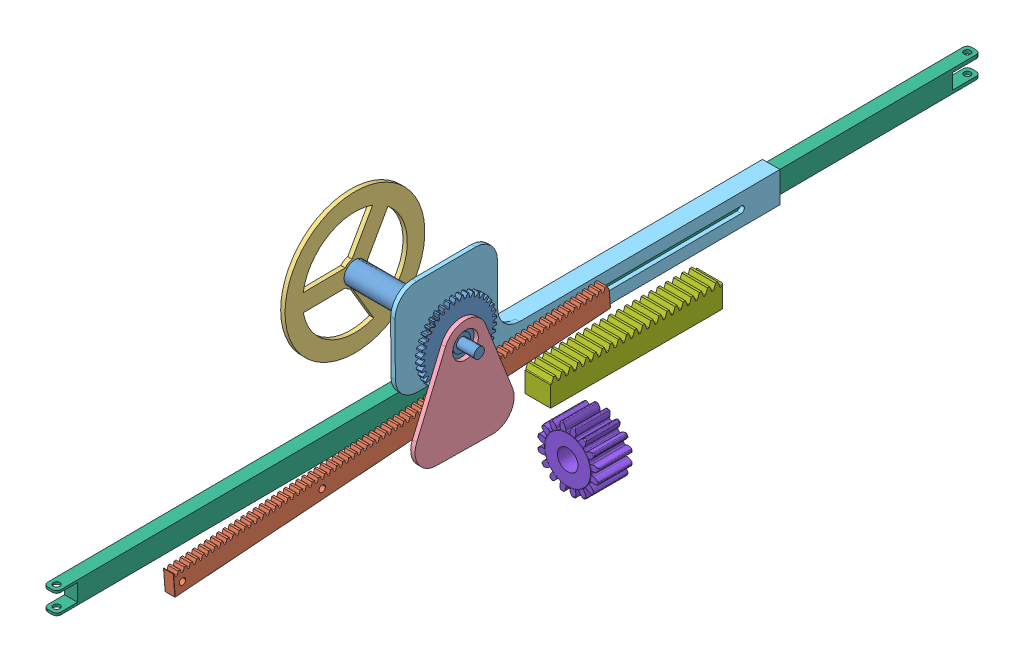
SolidWorks assembly ProgressiveSteering, configuration Default. Lengths in mm.
Overall size (91.09 164.43 537.27).
8 component instances, 8 part files, 22 mates.
Components (placement in the parent):
- SI_sdpsi_s1268z-024s040-2: SI_sdpsi_s1268z-024s040 [Default] at (1.5875 -10.9322 -6.4635) x (1 0 0) z (0 0.508936 -0.860805) size (65.8 44.45 44.45)
- SI_sdpsi_s1811y-rc-1a-1: SI_sdpsi_s1811y-rc-1a [Default] at (1.5875 -40.523 33.7269) x (0 -0.075237 0.997166) z (-1 0 0) size (254.01 12.19 10.01)
- steering wheel-1: steering wheel [Default] at (-55.245 0 0) x (0 -0.508936 0.860805) z (1 0 0) size (81.28 81.28 2.54)
- Part1^ProgressiveSteering-1: Part1^ProgressiveSteering [Default] at (7.0409 -36.8131 39.9889) x (0 0.013013 0.999915) z (-1 0 0) size (57.65 65.11 10.92) (virtual)
- slot-2: slot [Default] at (-16.3313 -50.6873 -22.7502) x (0 -0.006116 0.999981) z (-1 0 0) size (223.58 68.29 10.16)
- steering bar-1: steering bar [Default] at (-3.8735 -39.6305 140.3381) x (-1 0 0) z (0 0.006116 -0.999981) size (7.62 12.7 537.2)
- KHK-US_SRAF1_5-1000.stp-1: KHK-US_SRAF1_5-1000.stp [Default] at (-41.18 -102.411 -596.1689) size (16 15.5 100.5)
- 2664N392_Metal Gear - 20 Degree Pressure Angle-1: 2664N392_Metal Gear - 20 Degree Pressure Angle [2664N392] at (20.0282 -85.4641 -57.9863) size (35.44 35.44 20.17)
Mates (geometry in assembly coordinates):
- Coincident6: coincident anti-aligned: circle of SI_sdpsi_s1268z-024s040-2
- Coincident8: coincident: point of SI_sdpsi_s1268z-024s040-2; point of assembly
- Coincident13: coincident anti-aligned: plane of SI_sdpsi_s1268z-024s040-2 through (1.5875 -10.9322 -6.4635) normal (1 0 0); plane of SI_sdpsi_s1811y-rc-1a-1 through (1.5875 -40.523 33.7269) normal (-1 0 0)
- Distance1: distance = 21.082 mm: line of assembly; point of SI_sdpsi_s1268z-024s040-2; line of SI_sdpsi_s1811y-rc-1a-1 through (1.5875 -44.8095 163.1218) axis (0 0.075237 -0.997166)
- RackPinionMate2: rack pinion = 45.212 mm: line of SI_sdpsi_s1811y-rc-1a-1 through (-1.3335 -36.9296 -93.2356) axis (0 -0.075237 0.997166); cylinder of SI_sdpsi_s1268z-024s040-2 through (0 -10.9322 -6.4635) axis (1 0 0) radius 22.225
- Concentric6: concentric anti-aligned: cylinder of SI_sdpsi_s1268z-024s040-2 through (-50.8 0 0) axis (1 0 0) radius 6.35; cylinder of steering wheel-1 through (-50.8 0 0) axis (-1 0 0) radius 7.62
- Coincident21: coincident anti-aligned: plane of SI_sdpsi_s1268z-024s040-2 through (-50.8 0 0) normal (-1 0 0); plane of steering wheel-1 through (-50.8 0 0) normal (1 0 0)
- Coincident22: coincident: line of SI_sdpsi_s1268z-024s040-2 through (0 -29.8358 -17.6399) axis (0 0.860805 0.508936); plane of steering wheel-1 through (-55.245 0 0) normal (0 -0.508936 0.860805)
- Distance6: distance = 3.175 mm aligned: plane of slot-1 through (7.0485 -3.175 -260.805) normal (0 1 0)
- Concentric8: concentric anti-aligned: cylinder of Part1^ProgressiveSteering-1 through (96.8058 -27.6971 14.6022) axis (-1 0 0) radius 7.5; cylinder of 4668K121_Permanently Lubricated Stainless Steel Ball Bearing-3 through (4.5085 -27.4311 18.3355) axis (1 0 0) radius 7.5
- Coincident29: coincident anti-aligned: plane of Part1^ProgressiveSteering-1 through (7.0409 -10.9322 -6.4635) normal (1 0 0); plane of 4668K121_Permanently Lubricated Stainless Steel Ball Bearing-3 through (4.5085 -30.9404 20.5036) normal (1 0 0)
- Tangent2: tangent anti-aligned: plane of SI_sdpsi_s1811y-rc-1a-1 through (4.5085 -37.0467 -93.3718) normal (0 -0.997166 -0.075237); cylinder of 4668K121_Permanently Lubricated Stainless Steel Ball Bearing-3 through (4.5085 -27.4311 18.3355) axis (1 0 0) radius 7.5
- Distance7: distance = 25.4 mm: plane of slot-1 through (7.0485 -34.2791 -85.7379) normal (1 0 0); plane of SI_sdpsi_s1811y-rc-1a-1 through (-1.3335 -14.2012 -44.3268) normal (-1 0 0)
- Distance8: distance = 12.7 mm: plane of assembly through (0 0 0) normal (1 0 0); plane of assembly; plane of slot-1 through (7.0485 -34.2791 -85.7379) normal (1 0 0)
- Concentric9: concentric aligned: circle of SI_sdpsi_s1268z-024s040-2; circle of Part1^ProgressiveSteering-1
- Coincident32: coincident anti-aligned: plane of SI_sdpsi_s1811y-rc-1a-1 through (4.5085 -40.523 33.7269) normal (1 0 0); plane of Part1^ProgressiveSteering-1 through (4.5085 -10.9322 -6.4635) normal (-1 0 0)
- Coincident35: coincident anti-aligned: plane of SI_sdpsi_s1811y-rc-1a-1 through (-1.3335 -40.523 33.7269) normal (-1 0 0); plane of slot-2 through (-1.3335 -50.6873 -22.7502) normal (1 0 0)
- Concentric10: concentric aligned: circle of SI_sdpsi_s1268z-024s040-2; circle of slot-2
- Slot1: slot anti-aligned: cylinder of SI_sdpsi_s1811y-rc-1a-1 through (-5.4915 -31.8825 -88.2188) axis (1 0 0) radius 1.8669; plane of slot-2 through (-1.3335 -29.4461 -175.1024) normal (0 -0.999981 -0.006116); cylinder of slot-2 through (-1.3335 -31.351 -175.1141) axis (-1 0 0) radius 1.905
- Concentric11: concentric anti-aligned: circle of SI_sdpsi_s1811y-rc-1a-1; circle of steering bar-1
- Coincident38: coincident anti-aligned: plane of slot-2 through (-11.4935 -24.863 -197.6626) normal (0 -0.999981 -0.006116); plane of steering bar-1 through (-3.8735 -24.1345 -316.7757) normal (0 0.999981 0.006116)
- Coincident39: coincident anti-aligned: plane of slot-2 through (-3.8735 -50.6873 -22.7502) normal (-1 0 0); plane of steering bar-1 through (-3.8735 -36.8342 -316.8534) normal (1 0 0)
